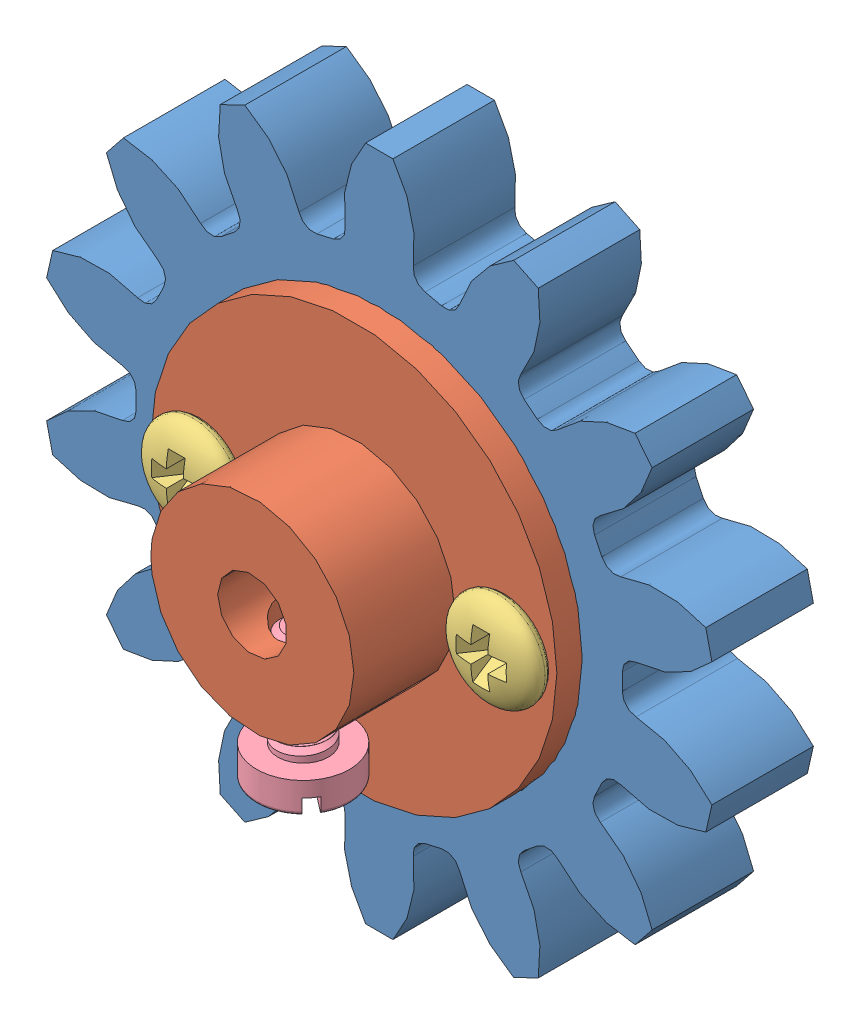
SolidWorks assembly engrenage-complet, configuration Défaut. Lengths in mm.
Overall size (39.32 40 14.36).
5 component instances, 4 part files, 9 mates.
Components (placement in the parent):
- engrenage-1: engrenage [Défaut] at (1.0609 0.1936 0) size (39.32 40 6)
- engrenage-bague_arret-1: engrenage-bague_arret [Défaut] at (-0.3178 -0.3667 13.5) x (-1 0 0) z (0 0 -1) size (24 24 8)
- vis-tc-m3x6.5-1: vis-tc-m3x6.5 [Défaut] at (8.6822 -0.3667 1.1) x (1 0 0) z (0 -1 0) size (5.6 8.09 5.6)
- vis-tc-m3x6.5-2: vis-tc-m3x6.5 [Défaut] at (-9.3178 -0.3667 1.1) x (1 0 0) z (0 -1 0) size (5.6 8.09 5.6)
- vis-tc-m3x6-1: vis-tc-m3x6 [Défaut] at (-0.3178 -8.4167 10.5) x (-0.611546 0 0.791209) z (0.791209 0 0.611546) size (5.5 7.83 5.5)
Mates (geometry in assembly coordinates):
- Coïncidente1: coincident anti-aligned: line of 14 dents module 2.5 axe D4-1 through (-9.3178 -0.3667 4.5) axis (0 0 1); line of Bague d'arrêt 4x12x24-1 through (-9.3178 -0.3667 7.5) axis (0 0 -1)
- Coïncidente2: coincident anti-aligned: line of 14 dents module 2.5 axe D4-1 through (8.6822 -0.3667 4.5) axis (0 0 1); line of Bague d'arrêt 4x12x24-1 through (8.6822 -0.3667 7.5) axis (0 0 -1)
- Coïncidente3: coincident anti-aligned: plane of 14 dents module 2.5 axe D4-1 through (-0.3178 -0.3667 5.5) normal (0 0 1); plane of Bague d'arrêt 4x12x24-1 through (-0.3178 -0.3667 5.5) normal (0 0 -1)
- Coïncidente4: coincident aligned: line of Bague d'arrêt 4x12x24-1 through (8.6822 -0.3667 7.5) axis (0 0 -1); line of VIs TC 3 x 6.5-1 through (8.6822 -0.3667 7.5) axis (0 0 -1)
- Coïncidente5: coincident aligned: line of Bague d'arrêt 4x12x24-1 through (-9.3178 -0.3667 7.5) axis (0 0 -1); line of VIs TC 3 x 6.5-2 through (-9.3178 -0.3667 7.5) axis (0 0 -1)
- Coïncidente6: coincident anti-aligned: plane of Bague d'arrêt 4x12x24-1 through (-0.3178 -0.3667 7.5) normal (0 0 1); plane of VIs TC 3 x 6.5-1 through (8.6822 -0.3667 7.5) normal (0 0 -1)
- Coïncidente7: coincident anti-aligned: plane of Bague d'arrêt 4x12x24-1 through (-0.3178 -0.3667 7.5) normal (0 0 1); plane of VIs TC 3 x 6.5-2 through (-9.3178 -0.3667 7.5) normal (0 0 -1)
- Coïncidente8: coincident anti-aligned: line of Bague d'arrêt 4x12x24-1 through (-0.3178 -6.3667 10.5) axis (0 1 0); line of Vis TC M3X6-1 through (-0.3178 -2.9167 10.5) axis (0 -1 0)
- Tangent1: tangent anti-aligned: cylinder of Bague d'arrêt 4x12x24-1 through (-0.3178 -0.3667 13.5) axis (0 0 -1) radius 2.05; plane of Vis TC M3X6-1 through (-0.3178 -2.4167 10.5) normal (0 1 0)
